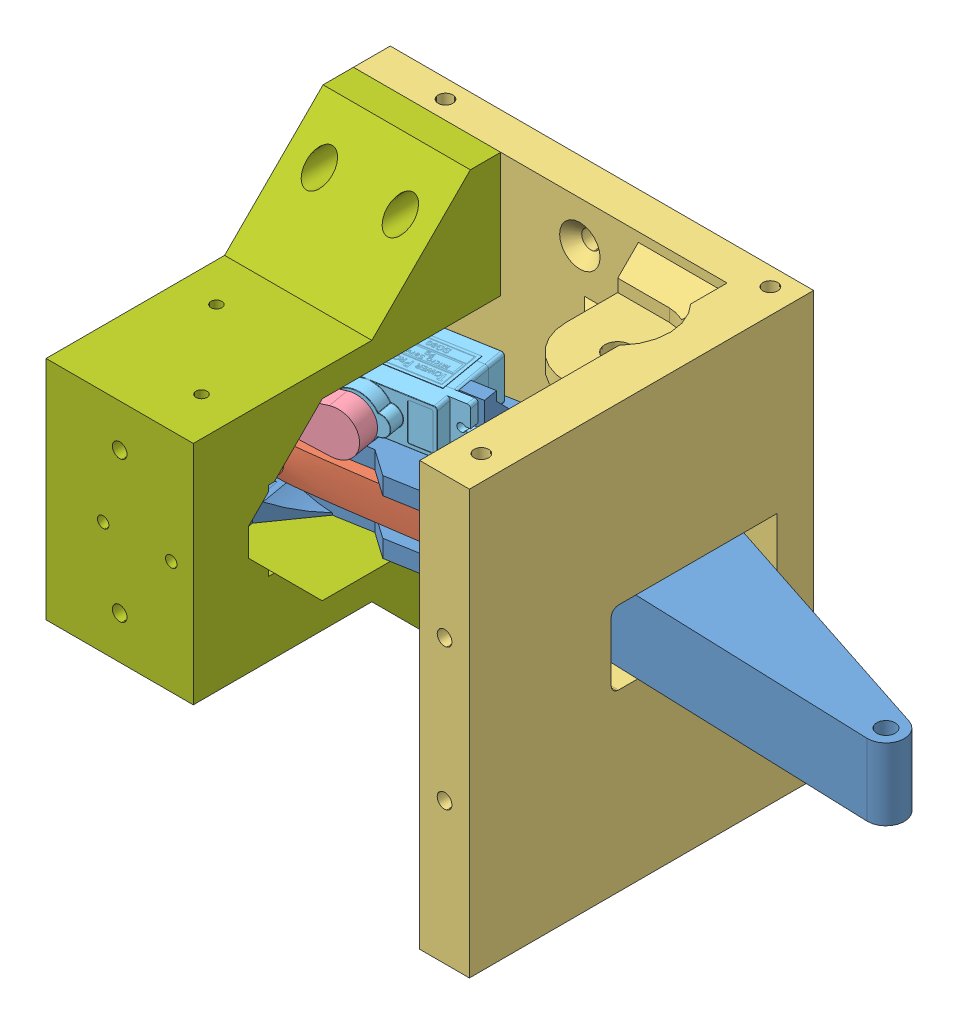
SolidWorks assembly v3Move, configuration Default. Lengths in mm.
Overall size (185.84 115 96.66).
7 component instances, 7 part files, 19 mates.
Components (placement in the parent):
- arm1-1: arm1 [Default] at (-4.8517 0 3.2659) x (0.985065 0 -0.172185) z (0 1 0) size (179.32 53.38 32)
- arm2-1: arm2 [Default] at (4.0275 0 -1.8967) x (0.991347 0 0.131269) z (0 1 0) size (87.35 50.5 9.5)
- base-1: base [Default] at origin size (115 115 93.5)
- servoArm-1: servoArm [Default] at (-33.6828 15.85 54.9521) x (0.984638 0.029438 -0.17211) z (0.172185 0 0.985065) size (31 12 6)
- SG90 - Micro Servo 9g - Tower Pro.1-1: SG90 - Micro Servo 9g - Tower Pro.1 [Peça] at (-32.2428 15.85 33.2805) x (0.985065 0 -0.172185) z (0 -1 0) size (32.1 29.95 12.4)
- SG90 - Micro Servo 9g - Tower Pro.2-1: SG90 - Micro Servo 9g - Tower Pro.2 [Peça] at (-33.6828 15.85 54.9521) x (0.984638 0.029438 -0.17211) z (0.028998 -0.999567 -0.005069) size (19.5 3.8 6.9)
- springBlock-1: springBlock [Default] at (-75 0 0) x (0 0 1) z (-1 0 0) size (83.5 115 40)
Mates (geometry in assembly coordinates):
- Coincident1: coordinate: point of base-1
- Coincident2: coincident aligned: plane of base-1 through (0 0 0) normal (0 0 1)
- Concentric1: concentric aligned: cylinder of arm1-1 through (16.4 9.75 29.6) axis (0 -1 0) radius 3.1; cylinder of base-1 through (16.4 20 29.6) axis (0 -1 0) radius 9.6
- Concentric2: concentric aligned: cylinder of arm1-1 through (16.4 9.75 29.6) axis (0 -1 0) radius 3.1; cylinder of base-1 through (16.4 20 29.6) axis (0 -1 0) radius 9.6
- Coincident3: coincident aligned: plane of base-1 through (-75 -57.5 10) normal (-1 0 0); plane of springBlock-1 through (-75 0 0) normal (-1 0 0)
- Coincident4: coincident anti-aligned: plane of base-1 through (0 0 10) normal (0 0 1); plane of springBlock-1 through (-35 -57.5 10) normal (0 0 -1)
- Coincident5: coincident aligned: plane of base-1 through (-75 57.5 10) normal (0 1 0); plane of springBlock-1 through (-35 57.5 10) normal (0 1 0)
- Coincident6: coincident aligned: plane of arm1-1 through (-4.8517 0 3.2659) normal (0 1 0)
- Coincident7: coincident aligned: plane of arm2-1 through (4.0275 0 -1.8967) normal (0 1 0)
- Parallel1: parallel anti-aligned: plane of arm1-1 through (105.0094 9.75 45.36) normal (0 1 0); plane of SG90 - Micro Servo 9g - Tower Pro.1-1 through (-23.8146 9.75 21.0974) normal (0 -1 0)
- Coincident8: coincident anti-aligned: plane of arm1-1 through (-14.0681 22.25 35.3318) normal (0.172185 0 0.985065); plane of SG90 - Micro Servo 9g - Tower Pro.1-1 through (-46.329 10.6 40.9708) normal (-0.172185 0 -0.985065)
- Coincident9: coincident anti-aligned: plane of arm1-1 through (105.0094 9.75 45.36) normal (0 1 0); plane of SG90 - Micro Servo 9g - Tower Pro.1-1 through (-23.8146 9.75 21.0974) normal (0 -1 0)
- Distance1: distance = 0.3 mm anti-aligned: plane of SG90 - Micro Servo 9g - Tower Pro.1-1 through (-20.274 10.6 36.4165) normal (0.985065 0 -0.172185); plane of arm1-1 through (-19.9785 22.25 36.3649) normal (-0.985065 0 0.172185)
- Concentric3: concentric aligned: cylinder of SG90 - Micro Servo 9g - Tower Pro.1-1 through (-33.9927 15.85 53.179) axis (0.172185 0 0.985065) radius 0.8; cylinder of SG90 - Micro Servo 9g - Tower Pro.2-1 through (-33.6828 15.85 54.9521) axis (0.172185 0 0.985065) radius 1.05
- Coincident10: coincident anti-aligned: plane of SG90 - Micro Servo 9g - Tower Pro.1-1 through (-33.9927 15.85 53.179) normal (0.172185 0 0.985065); plane of SG90 - Micro Servo 9g - Tower Pro.2-1 through (-33.9927 15.85 53.179) normal (-0.172185 0 -0.985065)
- Coincident11: coincident anti-aligned: plane of servoArm-1 through (-55.8371 15.1876 58.8246) normal (-0.172185 0 -0.985065); plane of SG90 - Micro Servo 9g - Tower Pro.2-1 through (-33.6828 15.85 54.9521) normal (0.172185 0 0.985065)
- Concentric4: concentric aligned: cylinder of servoArm-1 through (-34.3715 15.85 51.0119) axis (0.172185 0 0.985065) radius 3.75; cylinder of SG90 - Micro Servo 9g - Tower Pro.2-1 through (-33.9238 15.85 53.573) axis (0.172185 0 0.985065) radius 3.45
- Concentric5: concentric aligned: cylinder of servoArm-1 through (-48.2057 15.4364 53.43) axis (0.172185 0 0.985065) radius 2.3; cylinder of SG90 - Micro Servo 9g - Tower Pro.2-1 through (-47.758 15.4364 55.9912) axis (0.172185 0 0.985065) radius 2
- Concentric6: concentric aligned: cylinder of arm2-1 through (16.4 -4.75 29.6) axis (0 1 0) radius 9.6; cylinder of base-1 through (16.4 10 29.6) axis (0 1 0) radius 7.6
